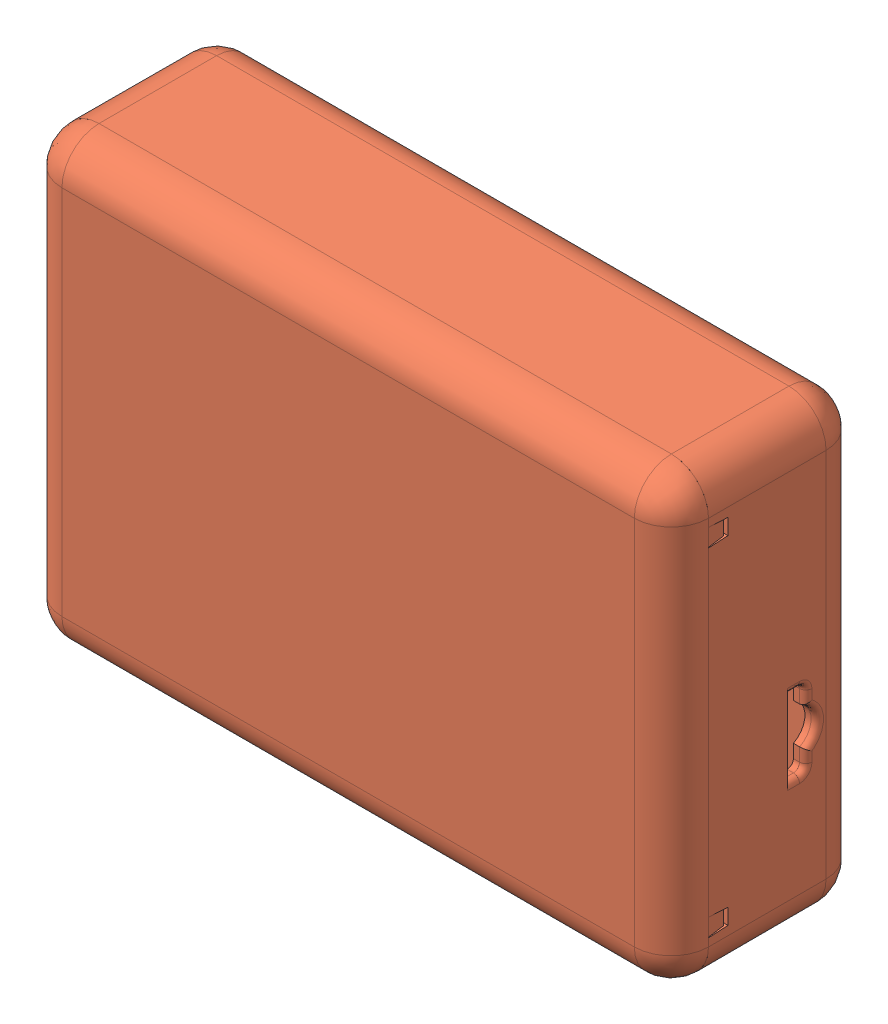
SolidWorks assembly Assem, configuration Default. Lengths in mm.
Overall size (106.2 72 31.24).
2 component instances, 2 part files, 3 mates.
Components (placement in the parent):
- Alarm-Clock-1: Alarm-Clock [Default] at origin size (103.95 61.59 24.42)
- case-1: case [Default] at (50 30.7925 -14.3) size (104.5 72 31)
Mates (geometry in assembly coordinates):
- Symmetric1: symmetric aligned: plane of Alarm-Clock-1 through (100 61.585 0) normal (0 1 0); plane of Alarm-Clock-1 through (0 0 0) normal (0 -1 0); plane of case-1 through (50 30.7925 -14.3) normal (0 1 0)
- Symmetric2: symmetric aligned: plane of Alarm-Clock-1 through (0 61.585 0) normal (-1 0 0); plane of Alarm-Clock-1 through (100 0 0) normal (1 0 0); plane of case-1 through (50 30.7925 -14.3) normal (1 0 0)
- Coincident2: coincident anti-aligned: plane of Alarm-Clock-1 through (50 30.7925 0) normal (0 0 -1); plane of case-1 through (2.9134 4.1247 0) normal (0 0 1)
